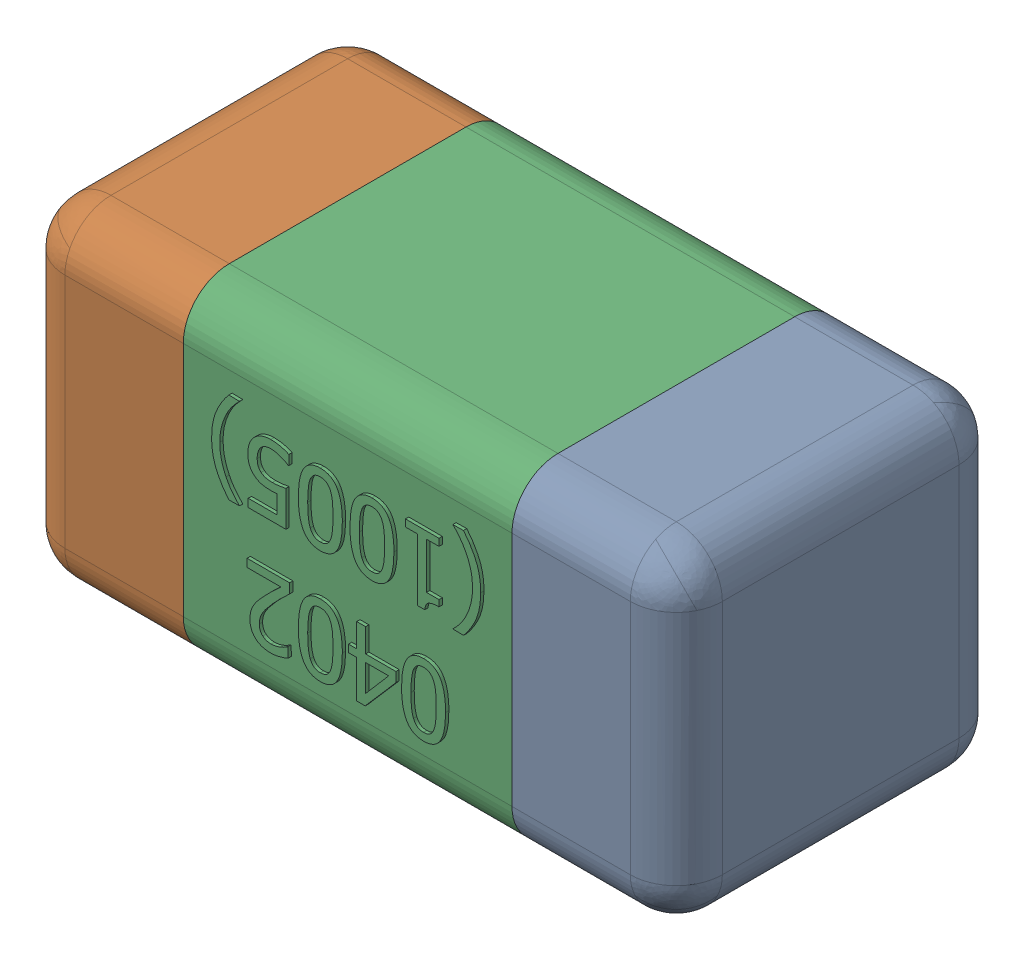
SolidWorks assembly C9, configuration Standard. Lengths in mm.
Overall size (1.01 0.51 0.51).
4 component instances, 3 part files, 0 mates.
Components (placement in the parent):
- C9-subassembly-1-1: C9-subassembly-1 [Standard] at (3.2999 11.8 0) x (-1 0 0) z (0 0 1) size (1.01 0.51 0.51)
  - User Library-0402_Cap-1: User Library-0402_Cap [Standard] at origin size (0.26 0.51 0.51)
  - User Library-0402_Cap-1-1: User Library-0402_Cap-1 [Standard] at origin size (0.26 0.5 0.51)
  - User Library-0402_Cap-2-1: User Library-0402_Cap-2 [Standard] at origin size (0.5 0.5 0.51)
